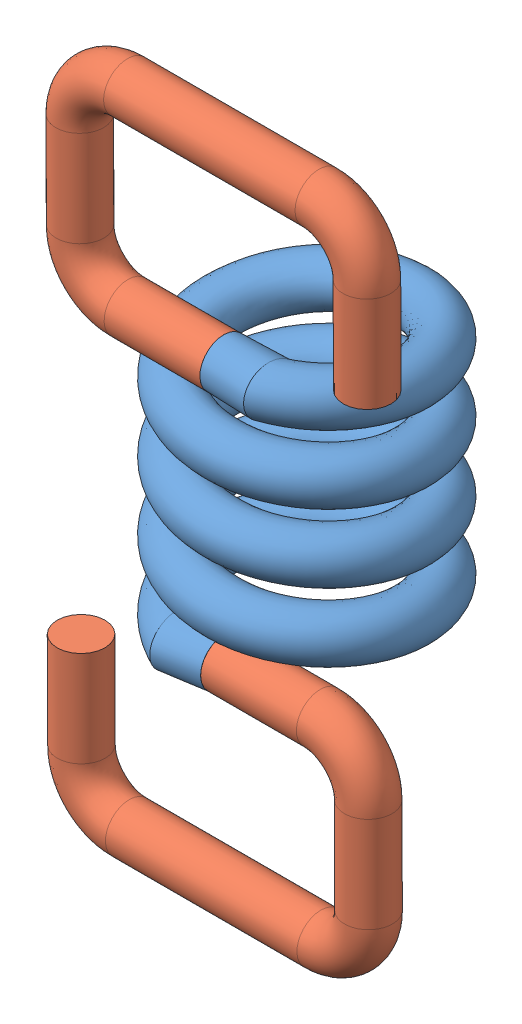
SolidWorks assembly Spring Assembly, configuration Default. Lengths in mm.
Overall size (35 72.14 30.13).
3 component instances, 2 part files, 3 mates.
Components (placement in the parent):
- Spring-1: Spring [Default] at (1.0157 11.384 37.7891) size (30.77 32.98 30.13)
- Spring hook 2-1: Spring hook 2 [Default] at (16.0157 44.3617 46.4701) x (-1 0 0) z (0 -0.999996 -0.002917) size (35 5 25)
- Spring hook 2-2: Spring hook 2 [Default] at (-13.9843 7.2381 46.3618) x (1 0 0) z (0 0.999996 0.002917) size (35 5 25)
Mates (geometry in assembly coordinates):
- Coincident1: coincident anti-aligned: circle of Spring-1; circle of Spring hook 2-1
- Coincident2: coincident aligned: circle of Spring-1; circle of Spring hook 2-2
- Concentric1: concentric aligned: cylinder of Spring hook 2-1 through (16.0157 44.3617 46.4701) axis (0 0.999996 0.002917) radius 2.5; cylinder of Spring hook 2-2 through (16.0157 -2.7619 46.3326) axis (0 0.999996 0.002917) radius 2.5
